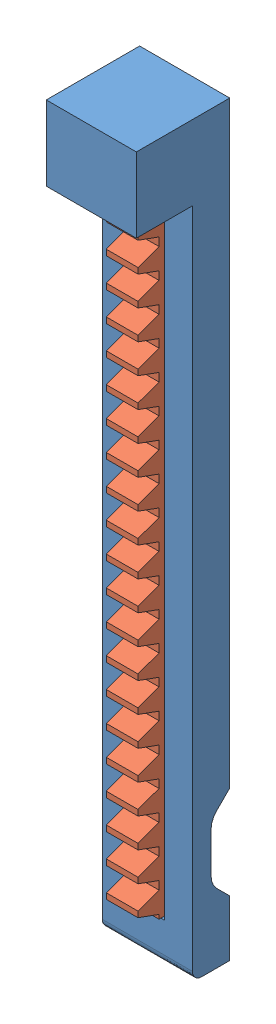
SolidWorks assembly Pinion, configuration Standard. Lengths in mm.
Overall size (9.65 80 10).
2 component instances, 2 part files, 4 mates.
Components (placement in the parent):
- Rack_spur_body-1: Rack_spur_body [Standard] at (-21.7173 12.203 0) size (9.65 80 10)
- Rack_spur_hercules-1: Rack_spur_hercules [Metric - Rack-spur - rectangular 1M 20PA 3.4FW 5.7PH 66L---SAll] at (-20.0173 -23.297 -2) x (0 1 0) z (1 0 0) size (66 6.7 3.4)
Mates (geometry in assembly coordinates):
- Deckungsgleich1: coincident aligned: plane of Rack_spur_body-1 through (-21.7173 12.203 -2) normal (0 0 -1); plane of Rack_spur_hercules-1 through (-23.4173 -23.297 -2) normal (0 0 -1)
- Abstand3: distance = 0.25 mm anti-aligned: plane of Rack_spur_hercules-1 through (-23.4173 42.703 -2) normal (0 1 0); plane of Rack_spur_body-1 through (-23.5673 42.953 -2) normal (0 -1 0)
- Abstand4: distance = 0.15 mm anti-aligned: plane of Rack_spur_hercules-1 through (-23.4173 -23.297 -2) normal (-1 0 0); plane of Rack_spur_body-1 through (-23.5673 42.953 -2) normal (1 0 0)
- Deckungsgleich2: coincident aligned: plane of Rack_spur_body-1 through (-21.7173 12.203 -2) normal (0 0 -1); plane of Rack_spur_hercules-1 through (-23.4173 -23.297 -2) normal (0 0 -1)
